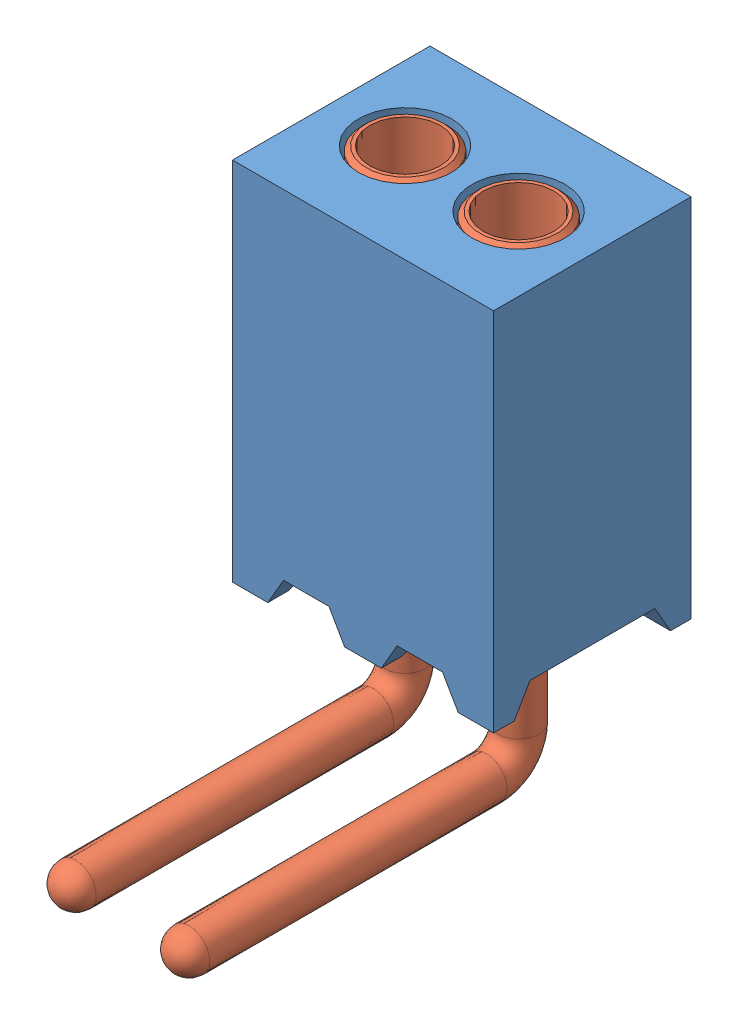
SolidWorks assembly mill-max-851-93-002-20-001000, configuration Default. Lengths in mm.
Overall size (2.92 5.54 5.02).
3 component instances, 2 part files, 0 mates.
Components (placement in the parent):
- mill-max-851-93-002-20-001000_P8XX-18-013-02-000000(P802-18-013-02-000000)-1: mill-max-851-93-002-20-001000_P8XX-18-013-02-000000(P802-18-013-02-000000) [Default] at origin size (2.92 4.09 2.21)
- mill-max-851-93-002-20-001000_4890(4890-1-00-53-00-00-03-4)-1: mill-max-851-93-002-20-001000_4890(4890-1-00-53-00-00-03-4) [Default] at (0.8255 0 -1.1049) x (0 -1 0) z (1 0 0) size (5.54 4.45 1.07)
- mill-max-851-93-002-20-001000_4890(4890-1-00-53-00-00-03-4)-2: mill-max-851-93-002-20-001000_4890(4890-1-00-53-00-00-03-4) [Default] at (2.0955 0 -1.1049) x (0 -1 0) z (1 0 0) size (5.54 4.45 1.07)
